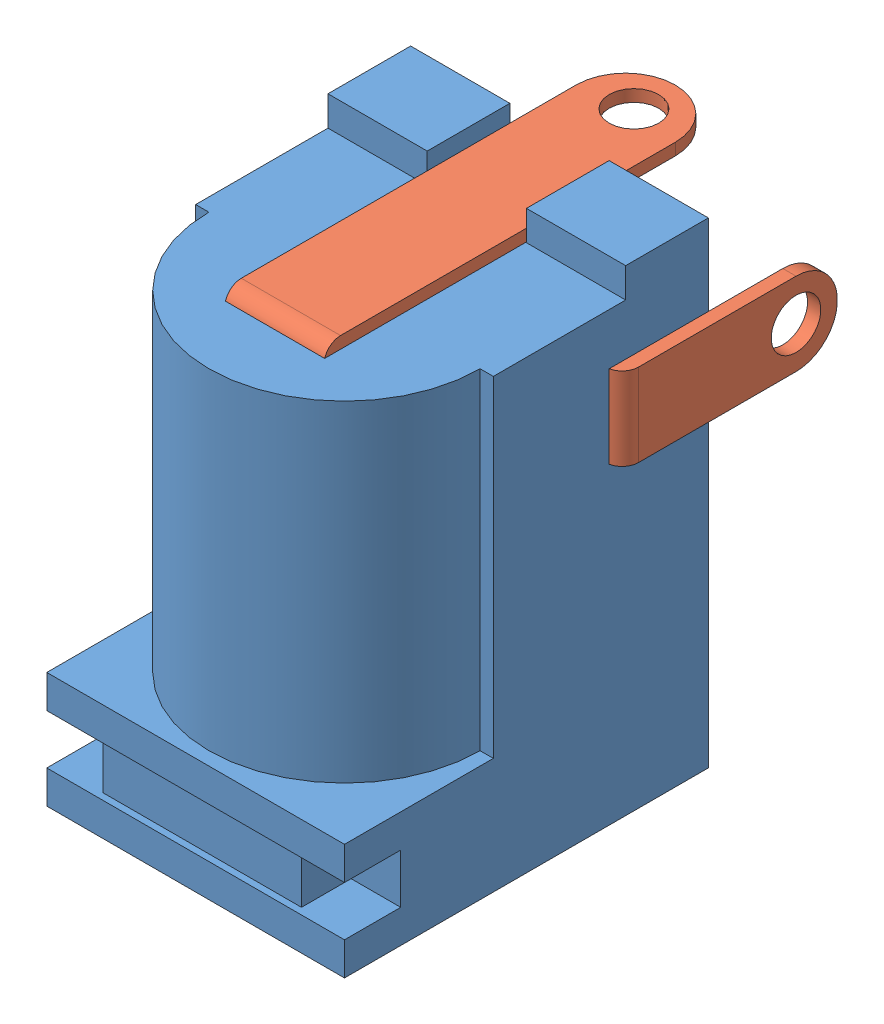
SolidWorks assembly User Library-PJ-002AH, configuration Default. Lengths in mm.
Overall size (9.4 14.4 14.5).
2 component instances, 2 part files, 0 mates.
Components (placement in the parent):
- User Library-PJ-002AH_Body-1: User Library-PJ-002AH_Body [Default] at (-7.4 -9.95 6.55) x (0 -1 0) z (-1 0 0) size (14.4 11 9)
- User Library-PJ-002AH_Pad-1: User Library-PJ-002AH_Pad [Default] at (-7.4 -9.95 6.55) x (0 -1 0) z (-1 0 0) size (12.88 12.1 6.4)
